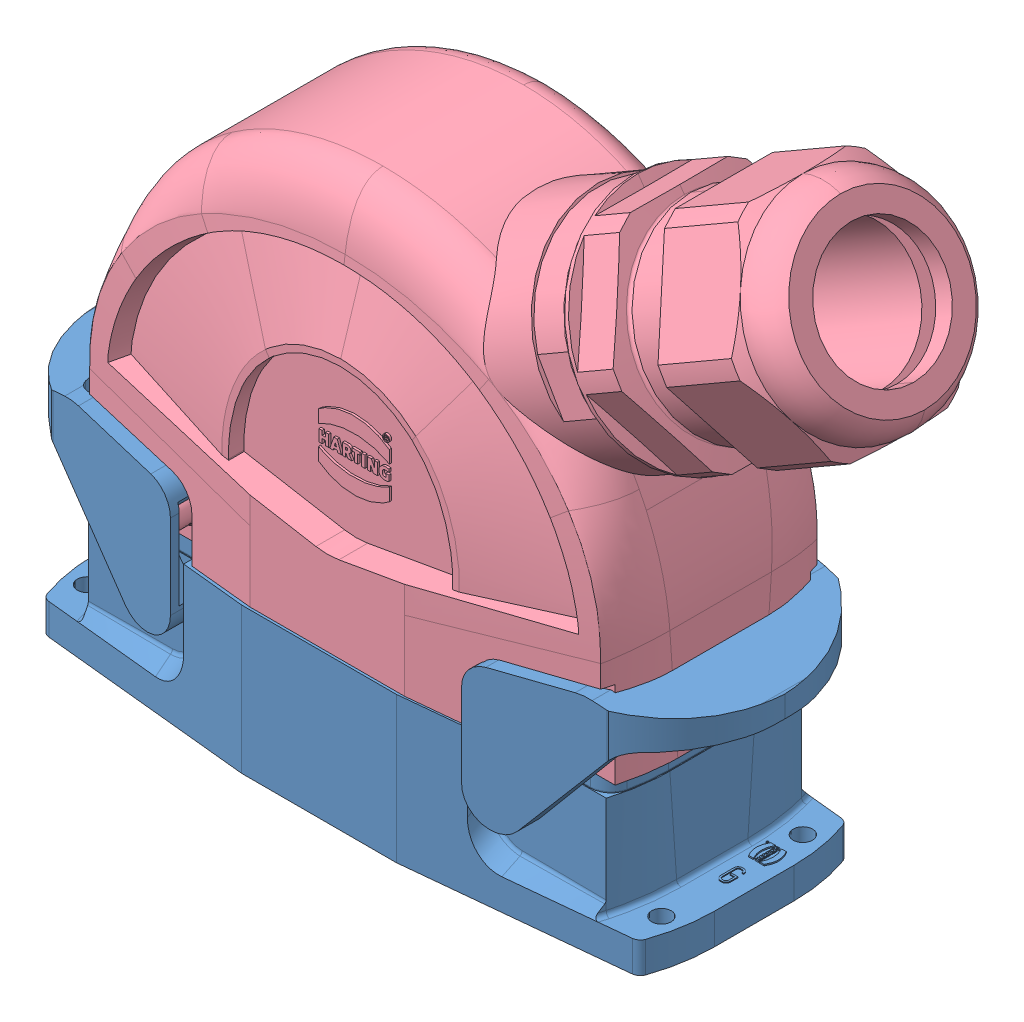
SolidWorks assembly Harting Mod.24-HSE-M40, configuration Default. Lengths in mm.
Overall size (185.57 158.35 76.54).
16 component instances, 4 part files, 12 mates.
Components (placement in the parent):
- 19410240301_100198179MOD000C-HOUSING-1: 19410240301_100198179MOD000C-HOUSING [Default] at origin size (154.05 52.02 60.84)
- 09140052601_100548017MOD000C.stp-1: 09140052601_100548017MOD000C.stp [Default] at (-43.15 34.9 0) x (-1 0 0) z (0 -1 0) size (14.7 34.2 34.4)
- 09140052701_100548140MOD000C-1: 09140052701_100548140MOD000C [Default] at (-43.15 -15.2 0) x (1 0 0) z (0 1 0) size (14.7 34.2 36.4)
- 19411240523_100556387MOD000C-HOUSING-1: 19411240523_100556387MOD000C-HOUSING [Default] at (1.9 -19.75 0) x (1 0 0) z (0 1 0) size (167.15 76.54 124.97)
- 09140052701_100548140MOD000C-2: 09140052701_100548140MOD000C [Default] at (-28.65 -15.2 0) x (1 0 0) z (0 1 0) size (14.7 34.2 36.4)
- 09140052701_100548140MOD000C-3: 09140052701_100548140MOD000C [Default] at (-14.15 -15.2 0) x (1 0 0) z (0 1 0) size (14.7 34.2 36.4)
- 09140052701_100548140MOD000C-4: 09140052701_100548140MOD000C [Default] at (0.35 -15.2 0) x (1 0 0) z (0 1 0) size (14.7 34.2 36.4)
- 09140052701_100548140MOD000C-5: 09140052701_100548140MOD000C [Default] at (14.85 -15.2 0) x (1 0 0) z (0 1 0) size (14.7 34.2 36.4)
- 09140052701_100548140MOD000C-6: 09140052701_100548140MOD000C [Default] at (29.35 -15.2 0) x (1 0 0) z (0 1 0) size (14.7 34.2 36.4)
- 09140052701_100548140MOD000C-7: 09140052701_100548140MOD000C [Default] at (43.85 -15.2 0) x (1 0 0) z (0 1 0) size (14.7 34.2 36.4)
- 09140052601_100548017MOD000C.stp-2: 09140052601_100548017MOD000C.stp [Default] at (-28.65 34.9 0) x (-1 0 0) z (0 -1 0) size (14.7 34.2 34.4)
- 09140052601_100548017MOD000C.stp-3: 09140052601_100548017MOD000C.stp [Default] at (-14.15 34.9 0) x (-1 0 0) z (0 -1 0) size (14.7 34.2 34.4)
- 09140052601_100548017MOD000C.stp-4: 09140052601_100548017MOD000C.stp [Default] at (0.35 34.9 0) x (-1 0 0) z (0 -1 0) size (14.7 34.2 34.4)
- 09140052601_100548017MOD000C.stp-5: 09140052601_100548017MOD000C.stp [Default] at (14.85 34.9 0) x (-1 0 0) z (0 -1 0) size (14.7 34.2 34.4)
- 09140052601_100548017MOD000C.stp-6: 09140052601_100548017MOD000C.stp [Default] at (29.35 34.9 0) x (-1 0 0) z (0 -1 0) size (14.7 34.2 34.4)
- 09140052601_100548017MOD000C.stp-7: 09140052601_100548017MOD000C.stp [Default] at (43.85 34.9 0) x (-1 0 0) z (0 -1 0) size (14.7 34.2 34.4)
Mates (geometry in assembly coordinates):
- Coincident1: coincident aligned: plane of 19410240301_100198179MOD000C-HOUSING-1 through (0 0 0) normal (0 0 1)
- Coincident2: coincident aligned: plane of 19410240301_100198179MOD000C-HOUSING-1 through (0 0 0) normal (0 1 0)
- Coincident3: coincident aligned: plane of 19410240301_100198179MOD000C-HOUSING-1 through (0 0 0) normal (1 0 0)
- Coincident4: coincident anti-aligned: plane of 19410240301_100198179MOD000C-HOUSING-1 through (-49.105 11.175 -17.1) normal (0 0 1); plane of 09140052701_100548140MOD000C-1 through (-39.3 -15.385 -17.1) normal (0 0 -1)
- Coincident5: coincident anti-aligned: plane of 19410240301_100198179MOD000C-HOUSING-1 through (-47.65 10.95 15.525) normal (1 0 0); plane of 09140052701_100548140MOD000C-1 through (-47.65 -12.5 15.15) normal (-1 0 0)
- Coincident6: coincident anti-aligned: plane of 19410240301_100198179MOD000C-HOUSING-1 through (-42.455 -11.5 17.2) normal (0 -1 0); plane of 09140052701_100548140MOD000C-1 through (-39.55 -11.5 14.2) normal (0 1 0)
- Coincident7: coincident anti-aligned: plane of 09140052601_100548017MOD000C.stp-1 through (-47 35.085 -17.1) normal (0 0 -1); plane of 19411240523_100556387MOD000C-HOUSING-1 through (-40.95 35.35 -17.1) normal (0 0 1)
- Coincident8: coincident anti-aligned: plane of 09140052601_100548017MOD000C.stp-1 through (-46.65 34.9 -15.15) normal (0 1 0); plane of 19411240523_100556387MOD000C-HOUSING-1 through (50.55 34.9 -15.6) normal (0 -1 0)
- Coincident9: coincident anti-aligned: plane of 09140052601_100548017MOD000C.stp-1 through (-38.65 32 13.15) normal (1 0 0); plane of 19411240523_100556387MOD000C-HOUSING-1 through (-38.65 10.35 17.1) normal (-1 0 0)
- LimitDistance1: limit distance = 0 mm anti-aligned: plane of 09140052601_100548017MOD000C.stp-1 through (-40.975 9.85 15.75) normal (0 -1 0); plane of 09140052701_100548140MOD000C-1 through (-36.5725 9.85 15.73) normal (0 1 0)
- Coincident12: coincident aligned: plane of 09140052601_100548017MOD000C.stp-1 through (-42.175 8.4325 -15.15) normal (0 0 -1); plane of 09140052701_100548140MOD000C-1 through (-35.825 -18.7 -15.15) normal (0 0 -1)
- Concentric1: concentric anti-aligned: cylinder of 09140052601_100548017MOD000C.stp-1 through (-46.475 7.65 11.6) axis (0 1 0) radius 1.25; cone of 09140052701_100548140MOD000C-1 through (-46.475 18 11.6) axis (0 -1 0)
